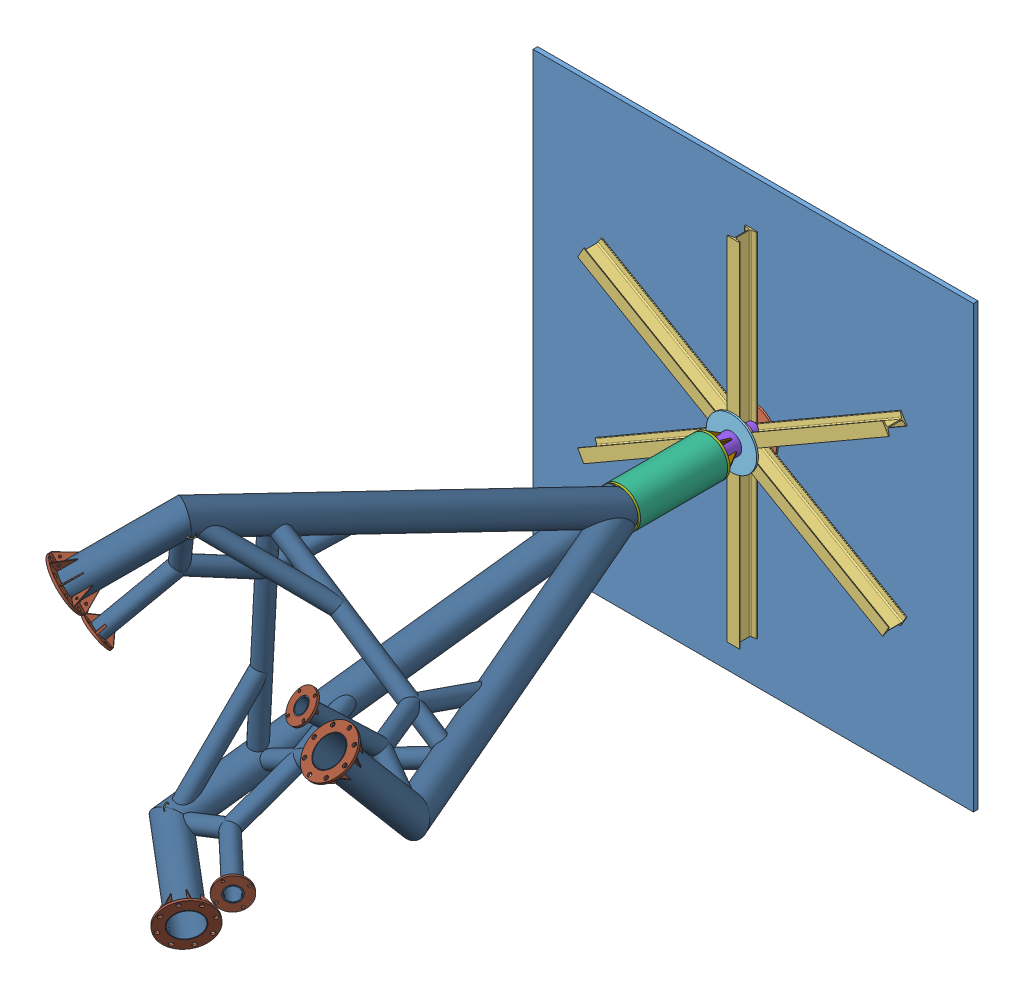
SolidWorks assembly central_structure, configuration Default. Lengths in mm.
Overall size (2438.4 2438.4 3268.86).
35 component instances, 14 part files, 19 mates.
Components (placement in the parent):
- reference_cubes-1: reference_cubes [Default] at origin size (10937.47 5524.84 3894.08) (hidden)
- scaffolding^central_structure-1: scaffolding^central_structure [Default] at (0 0 -124.5199) x (-1 0 0) z (0 1 0) size (2438.4 25.4 2438.4) (virtual)
  - reference_ground^scaffolding_central_structure-1: reference_ground^scaffolding_central_structure [Default] x (-1 0 0) z (0 1 0) size (2438.4 2438.4 25.4) (virtual)
- ground_anchor-1: ground_anchor [Default] at (0 0 -124.5199) x (-1 0 0) z (0 1 0) size (1722.09 120.65 1949.45)
  - Copy of ground_anchor_ref^ground_anchor-1: Copy of ground_anchor_ref^ground_anchor [Default] at origin size (279.4 0 279.4) (virtual)
  - low_plate^ground_anchor-1: low_plate^ground_anchor [Default] at origin size (279.4 9.53 279.4) (virtual)
  - S Section_AI-1: S Section_AI [S4x7.7x36] at (-33.8201 9.525 -517.525) size (67.64 101.6 914.4)
  - S Section_AI-3: S Section_AI [S4x7.7x36] at (-465.0998 9.525 -229.4734) x (0.5 0 -0.866025) z (0.866025 0 0.5) size (67.64 101.6 914.4)
  - S Section_AI-4: S Section_AI [S4x7.7x36] at (-431.2797 9.525 288.0516) x (-0.5 0 -0.866025) z (0.866025 0 -0.5) size (67.64 101.6 914.4)
  - S Section_AI-5: S Section_AI [S4x7.7x36] at (33.8201 9.525 517.525) x (-1 0 0) z (0 0 -1) size (67.64 101.6 914.4)
  - S Section_AI-6: S Section_AI [S4x7.7x36] at (465.0998 9.525 229.4734) x (-0.5 0 0.866025) z (-0.866025 0 -0.5) size (67.64 101.6 914.4)
  - S Section_AI-7: S Section_AI [S4x7.7x36] at (431.2797 9.525 -288.0516) x (0.5 0 0.866025) z (-0.866025 0 0.5) size (67.64 101.6 914.4)
  - mid_plate^ground_anchor-2: mid_plate^ground_anchor [Default] at origin size (146.05 9.53 146.05) (virtual)
  - top_plate^ground_anchor-1: top_plate^ground_anchor [Default] at (0 111.125 0) x (-1 0 0) z (0 1 0) size (279.4 279.4 9.53) (virtual)
- base_pin^central_structure-1: base_pin^central_structure [Default] at (0 0 367.6051) x (1 0 0) z (0 -1 0) size (219.07 736.6 219.07) (virtual)
  - tube^base_pin_central_structure-1: tube^base_pin_central_structure [Default] at origin size (219.07 482.6 219.07) (virtual)
  - plate^base_pin_central_structure-1: plate^base_pin_central_structure [Default] at (0 -254 0) size (219.07 12.7 219.07) (virtual)
  - plate^base_pin_central_structure-2: plate^base_pin_central_structure [Default] at (0 241.3 0) size (219.07 12.7 219.07) (virtual)
  - pin^base_pin_central_structure-1: pin^base_pin_central_structure [Default] at (0 -368.3 0) size (114.3 228.6 114.3) (virtual)
  - gusset^base_pin_central_structure-1: gusset^base_pin_central_structure [Default] at (0 -241.3 0) x (-1 0 0) z (0 0 -1) size (52.39 88.9 9.53) (virtual)
  - gusset^base_pin_central_structure-2: gusset^base_pin_central_structure [Default] at (0 -241.3 0) x (-0.5 0 -0.866025) z (0.866025 0 -0.5) size (52.39 88.9 9.53) (virtual)
  - gusset^base_pin_central_structure-3: gusset^base_pin_central_structure [Default] at (0 -241.3 0) x (0.5 0 -0.866025) z (0.866025 0 0.5) size (52.39 88.9 9.53) (virtual)
  - gusset^base_pin_central_structure-4: gusset^base_pin_central_structure [Default] at (0 -241.3 0) size (52.39 88.9 9.53) (virtual)
  - gusset^base_pin_central_structure-5: gusset^base_pin_central_structure [Default] at (0 -241.3 0) x (0.5 0 0.866025) z (-0.866025 0 0.5) size (52.39 88.9 9.53) (virtual)
  - gusset^base_pin_central_structure-6: gusset^base_pin_central_structure [Default] at (0 -241.3 0) x (-0.5 0 0.866025) z (-0.866025 0 -0.5) size (52.39 88.9 9.53) (virtual)
- tubes^central_structure-1: tubes^central_structure [Default<As Machined>] at origin size (1730.45 1786.14 2430.89) (virtual)
- pipe_flange-4: pipe_flange [Default] at (-40.8618 -842.5697 2971.914) x (-0.647876 -0.272848 0.711204) z (-0.761452 0.20604 -0.614604) size (279.4 279.4 111.05)
- pipe_flange-5: pipe_flange [Default] at (-709.2559 456.6722 2971.914) x (0.087644 0.697501 0.711204) z (0.559162 0.556417 -0.614604) size (279.4 279.4 111.05)
- pipe_flange-6: pipe_flange [Default] at (750.1177 385.8975 2971.914) x (0.560231 -0.424653 0.711204) z (0.20229 -0.762457 -0.614604) size (279.4 279.4 111.05)
- pipe_flange-10: pipe_flange [Sch40_3_inch] at (125.9153 -655.6721 2881.7665) x (-0.595866 -0.523692 0.608844) z (-0.726669 0.028829 -0.686383) size (177.8 177.8 57.15)
- pipe_flange-11: pipe_flange [Sch40_3_inch] at (-630.7864 218.7903 2881.7665) x (-0.155598 0.777881 0.608844) z (0.388301 0.614899 -0.686383) size (177.8 177.8 57.15)
- pipe_flange-12: pipe_flange [Sch40_3_inch] at (504.8711 436.8819 2881.7665) x (0.751464 -0.254189 0.608844) z (0.338368 -0.643728 -0.686383) size (177.8 177.8 57.15)
- positioning_ring^central_structure-1: positioning_ring^central_structure [Default] at (-467.1227 -648.6433 2658.0072) x (-0.32518 0.316298 -0.891186) z (0.945415 0.129823 -0.298891) size (41.91 20.96 5.08) (virtual)
- positioning_ring^central_structure-2: positioning_ring^central_structure [Default] at (-328.1802 728.8618 2658.0072) x (0.436513 0.123465 -0.891186) z (-0.360278 -0.883665 -0.298891) size (41.91 20.96 5.08) (virtual)
- positioning_ring^central_structure-3: positioning_ring^central_structure [Default] at (795.303 -80.2185 2658.0072) x (-0.111332 -0.439764 -0.891186) z (-0.585137 0.753842 -0.298891) size (41.91 20.96 5.08) (virtual)
Mates (geometry in assembly coordinates):
- Coincident4: coincident anti-aligned: plane of ? through (0 0 621.6051) normal (0 0 -1); plane of base_pin^central_structure-1/plate^base_pin_central_structure-2 through (0 0 621.6051) normal (0 0 1)
- Concentric2: concentric anti-aligned: cylinder of ? through (-40.8618 -842.5697 2971.914) axis (-0.761452 0.20604 -0.614604) radius 84.1375; cylinder of pipe_flange-4 through (-50.5323 -839.953 2964.1086) axis (0.761452 -0.20604 0.614604) radius 84.1375
- Coincident5: coincident aligned: plane of ? through (-40.8618 -842.5697 2971.914) normal (0.761452 -0.20604 0.614604); plane of pipe_flange-4 through (-40.8618 -842.5697 2971.914) normal (0.761452 -0.20604 0.614604)
- Coincident7: coincident aligned: plane of ? through (125.9153 -655.6721 2881.7665) normal (0.726669 -0.028829 0.686383); plane of pipe_flange-10 through (125.9153 -655.6721 2881.7665) normal (0.726669 -0.028829 0.686383)
- Concentric4: concentric anti-aligned: cylinder of ? through (125.9153 -655.6721 2881.7665) axis (-0.726669 0.028829 -0.686383) radius 44.45; cylinder of pipe_flange-10 through (116.6866 -655.306 2873.0495) axis (0.726669 -0.028829 0.686383) radius 44.45
- Coincident35: coordinate: point of ?
- Coincident15: coincident anti-aligned: plane of ? through (0 0 -114.9949) normal (0 0 1); plane of base_pin^central_structure-1/pin^base_pin_central_structure-1 through (0 0 -114.9949) normal (0 0 -1)
- Concentric20: concentric aligned: cylinder of ground_anchor-1/top_plate^ground_anchor-1 through (0 0 -3.8699) axis (0 0 -1) radius 57.15; cylinder of base_pin^central_structure-1/pin^base_pin_central_structure-1 through (0 0 113.6051) axis (0 0 -1) radius 57.15
- Coincident47: coincident aligned: plane of ? through (0 0 -124.5199) normal (0 1 0); plane of assembly through (0 0 0) normal (0 1 0)
- Coincident49: coordinate: point of ?; point of ?
- Coincident51: coincident aligned: line of ? through (-462.8295 -839.3341 2588.761) axis (-0.021157 0.939735 0.341249); line of positioning_ring^central_structure-1 through (-467.1227 -648.6433 2658.0072) axis (-0.021157 0.939735 0.341249)
- Tangent4: tangent anti-aligned: cylinder of ? through (-40.8618 -842.5697 2971.914) axis (-0.761452 0.20604 -0.614604) radius 84.1375; plane of positioning_ring^central_structure-1 through (-461.1345 -654.468 2674.4184) normal (0.021157 -0.939735 -0.341249)
- Tangent5: tangent anti-aligned: cylinder of ? through (-465.3426 -727.7103 2629.2954) axis (0.201813 0.338314 -0.919139) radius 84.1375; plane of positioning_ring^central_structure-1 through (-473.1109 -642.8187 2641.596) normal (0.021157 -0.939735 -0.341249)
- Perpendicular2: perpendicular: plane of ? through (787.6016 -766.0891 2158.4937) normal (0.32518 -0.316298 0.891186); plane of positioning_ring^central_structure-1 through (-467.1227 -648.6433 2658.0072) normal (0.945415 0.129823 -0.298891)
- Coincident53: coincident anti-aligned: plane of base_pin^central_structure-1/tube^base_pin_central_structure-1 through (0 0 367.6051) normal (0 -1 0); plane of ? through (0 0 0) normal (0 1 0)
- Coincident54: coincident aligned: plane of base_pin^central_structure-1/tube^base_pin_central_structure-1; plane of ? through (0 0 0) normal (1 0 0)
- Coincident55: coincident aligned: plane of ? through (-1535.468 -646.6512 1685.5551) normal (-0.647876 -0.272848 0.711204); plane of pipe_flange-4
- Coincident57: coincident anti-aligned: plane of ? through (-186.2882 463.9041 216.7065) normal (0.341901 -0.85142 -0.397729); unknown of pipe_flange-10
- positioning_ring_pattern: unknown: line of base_pin^central_structure-1/tube^base_pin_central_structure-1 through (0 0 608.9051) axis (0 0 -1)
